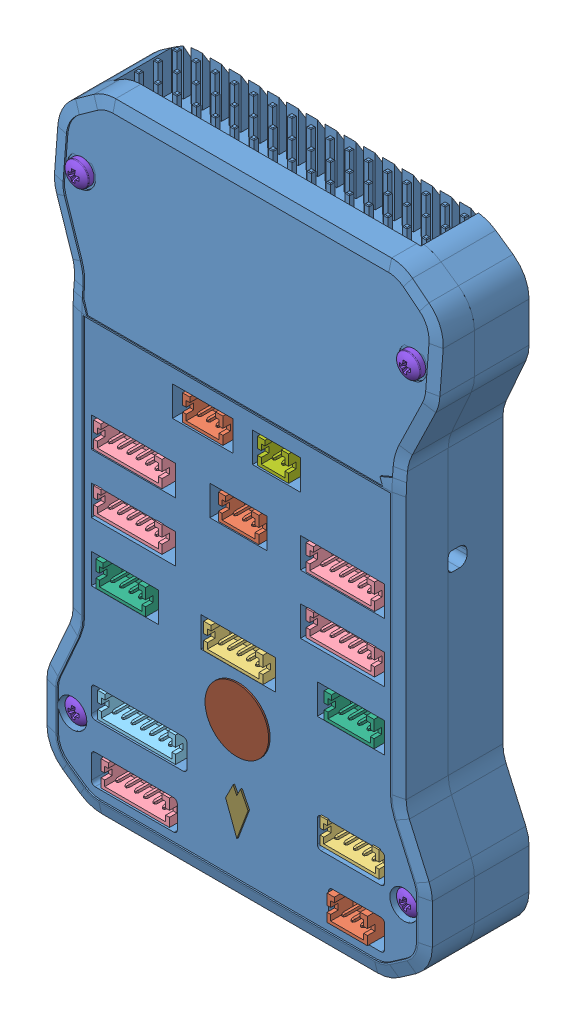
SolidWorks assembly Pixhawk, configuration Défaut. Lengths in mm.
Overall size (63.92 81.8 15).
24 component instances, 12 part files, 56 mates.
Components (placement in the parent):
- Pixhawk APM-1: Pixhawk APM [Défaut] at (-25.3722 -39.1501 0) size (51.5 81.8 15)
- DF13-3P-1.25DSA-1: DF13-3P-1.25DSA [Défaut] at (-25.6222 -101.0173 12.2305) x (0 -1 0) z (-1 0 0) size (3.4 6.6 5.4)
- DF13-5P-1.25DSA-1: DF13-5P-1.25DSA [Défaut] at (-24.0615 -92.547 12.2305) x (0 -1 0) z (-1 0 0) size (3.4 6.6 7.9)
- DF13-6P-1.25DSA-1: DF13-6P-1.25DSA [Défaut] at (-52.0766 -100.5605 12.2305) x (0 -1 0) z (-1 0 0) size (3.4 6.6 9.15)
- DF13-7P-1.25DSA-1: DF13-7P-1.25DSA [Défaut] at (-51.2619 -92.8659 12.2305) x (0 -1 0) z (-1 0 0) size (3.4 6.6 10.4)
- DF13-4P-1.25DSA-1: DF13-4P-1.25DSA [Défaut] at (-24.742 -77.7939 12.2305) x (0 -1 0) z (-1 0 0) size (3.4 6.6 6.65)
- DF13-4P-1.25DSA-2: DF13-4P-1.25DSA [Défaut] at (-55.2674 -77.7939 12.2305) x (0 -1 0) z (-1 0 0) size (3.4 6.6 6.65)
- DF13-5P-1.25DSA-2: DF13-5P-1.25DSA [Défaut] at (-39.5965 -77.7939 12.2305) x (0 -1 0) z (-1 0 0) size (3.4 6.6 7.9)
- DF13-6P-1.25DSA-2: DF13-6P-1.25DSA [Défaut] at (-24.6722 -69.4608 12.2305) x (0 -1 0) z (-1 0 0) size (3.4 6.6 9.15)
- DF13-6P-1.25DSA-3: DF13-6P-1.25DSA [Défaut] at (-24.6722 -61.8649 12.2305) x (0 -1 0) z (-1 0 0) size (3.4 6.6 9.15)
- DF13-6P-1.25DSA-4: DF13-6P-1.25DSA [Défaut] at (-53.0678 -69.4608 12.2305) x (0 -1 0) z (-1 0 0) size (3.4 6.6 9.15)
- DF13-6P-1.25DSA-5: DF13-6P-1.25DSA [Défaut] at (-53.0678 -61.8649 12.2305) x (0 -1 0) z (-1 0 0) size (3.4 6.6 9.15)
- DF13-3P-1.25DSA-2: DF13-3P-1.25DSA [Défaut] at (-40.1316 -61.8649 12.2305) x (0 -1 0) z (-1 0 0) size (3.4 6.6 5.4)
- DF13-2P-1.25DSA-1: DF13-2P-1.25DSA [Défaut] at (-36.1541 -52.7875 12.2305) x (0 -1 0) z (-1 0 0) size (3.4 6.6 4.15)
- DF13-3P-1.25DSA-3: DF13-3P-1.25DSA [Défaut] at (-44.932 -52.7875 12.2305) x (0 -1 0) z (-1 0 0) size (3.4 6.6 5.4)
- pan head cross recess screw_iso-1: pan head cross recess screw_iso [ISO 7045 - M1.6 x 3 - Z --- 3N] at (-3.2222 -8.1001 14.8) x (0 0 -1) z (1 0 0) size (4.27 3.2 3.2)
- pan head cross recess screw_iso-2: pan head cross recess screw_iso [ISO 7045 - M1.6 x 3 - Z --- 3N] at (-47.5222 -8.1001 14.8) x (0 0 -1) z (1 0 0) size (4.27 3.2 3.2)
- pan head cross recess screw_iso-3: pan head cross recess screw_iso [ISO 7045 - M1.6 x 3 - Z --- 3N] at (-3.2222 -70.2001 14.8) x (0 0 -1) z (1 0 0) size (4.27 3.2 3.2)
- pan head cross recess screw_iso-4: pan head cross recess screw_iso [ISO 7045 - M1.6 x 3 - Z --- 3N] at (-47.5222 -70.2001 14.8) x (0 0 -1) z (1 0 0) size (4.27 3.2 3.2)
- micro USB-2: micro USB [Défaut] at (-63.1127 -36.7397 13.3569) x (0 1 0) z (-1 0 0) size (21.93 8.87 21.44)
  - micro usb02-1: micro usb02 [Défaut] at (-14.4796 6.4719 -20.7085) size (6.9 2.16 4.2)
  - micro USB-1: micro USB [Défaut] at (-14.4796 6.4719 -16.0085) size (7.99 2.94 5.43)
- pièce10^Pixhawk-1: pièce10^Pixhawk [Défaut] at (-25.3722 -39.1501 14.5) size (8.5 8.5 0.5) (virtual)
- pièce11^Pixhawk-1: pièce11^Pixhawk [Défaut] at (-25.3722 -39.1501 14.5) size (3 6 0.5) (virtual)
Mates (geometry in assembly coordinates):
- Coïncidente1: coincident aligned: plane of Pixhawk APM-1 through (-25.3722 -39.1501 15) normal (0 0 1); plane of DF13-3P-1.25DSA-1 through (-7.1722 -76.9001 15) normal (0 0 1)
- Parallèle1: coincident anti-aligned: plane of Pixhawk APM-1 through (-5.8222 -77.2001 10) normal (0 1 0); plane of DF13-3P-1.25DSA-1 through (-23.427 -77.2001 14.6158) normal (0 -1 0)
- Coïncidente2: coincident aligned: plane of Pixhawk APM-1 through (-25.3722 -39.1501 15) normal (0 0 1); plane of DF13-5P-1.25DSA-1 through (-13.7615 -65.9798 15) normal (0 0 1)
- Parallèle2: parallel anti-aligned: plane of Pixhawk APM-1 through (-5.8222 -69.5001 10) normal (0 1 0); plane of DF13-5P-1.25DSA-1 through (-9.3663 -68.7298 14.6158) normal (0 -1 0)
- Coïncidente4: coincident aligned: plane of Pixhawk APM-1 through (-25.3722 -39.1501 15) normal (0 0 1); plane of DF13-6P-1.25DSA-1 through (-43.0266 -73.9933 15) normal (0 0 1)
- Parallèle3: parallel anti-aligned: plane of Pixhawk APM-1 through (-33.5222 -77.2001 10) normal (0 1 0); plane of DF13-6P-1.25DSA-1 through (-38.6314 -76.7433 14.6158) normal (0 -1 0)
- Coïncidente5: coincident aligned: plane of Pixhawk APM-1 through (-25.3722 -39.1501 15) normal (0 0 1); plane of DF13-7P-1.25DSA-1 through (-47.8119 -68.7487 15) normal (0 0 1)
- Parallèle5: parallel anti-aligned: plane of Pixhawk APM-1 through (-32.2222 -69.5001 10) normal (0 1 0); plane of DF13-7P-1.25DSA-1 through (-49.0667 -69.0487 14.6158) normal (0 -1 0)
- Coïncidente6: coincident aligned: plane of Pixhawk APM-1 through (-25.3722 -39.1501 15) normal (0 0 1); plane of DF13-4P-1.25DSA-2 through (-51.8174 -53.6767 15) normal (0 0 1)
- Parallèle6: parallel anti-aligned: plane of Pixhawk APM-1 through (-36.0222 -54.2001 10) normal (0 1 0); plane of DF13-4P-1.25DSA-2 through (-39.3222 -53.9767 14.6158) normal (0 -1 0)
- Coïncidente7: coincident aligned: plane of Pixhawk APM-1 through (-25.3722 -39.1501 15) normal (0 0 1); plane of DF13-4P-1.25DSA-1 through (-21.292 -53.6767 15) normal (0 0 1)
- Coïncidente8: coincident aligned: plane of DF13-4P-1.25DSA-1 through (-8.7968 -53.9767 14.6158) normal (0 -1 0); plane of DF13-4P-1.25DSA-2 through (-39.3222 -53.9767 14.6158) normal (0 -1 0)
- Coïncidente9: coincident aligned: plane of Pixhawk APM-1 through (-25.3722 -39.1501 15) normal (0 0 1); plane of DF13-5P-1.25DSA-2 through (-36.1465 -53.6767 15) normal (0 0 1)
- Coïncidente10: coincident aligned: plane of DF13-4P-1.25DSA-2 through (-39.3222 -53.9767 14.6158) normal (0 -1 0); plane of DF13-5P-1.25DSA-2 through (-24.9013 -53.9767 14.6158) normal (0 -1 0)
- Coïncidente12: coincident aligned: plane of Pixhawk APM-1 through (-25.3722 -39.1501 15) normal (0 0 1); plane of DF13-6P-1.25DSA-2 through (-21.2222 -45.3436 15) normal (0 0 1)
- Parallèle8: parallel anti-aligned: plane of Pixhawk APM-1 through (-5.8222 -46.3001 10) normal (0 1 0); plane of DF13-6P-1.25DSA-2 through (-11.227 -45.6436 14.6158) normal (0 -1 0)
- Coïncidente13: coincident aligned: plane of DF13-6P-1.25DSA-2 through (-21.2222 -45.3436 15) normal (0 0 1); plane of DF13-6P-1.25DSA-3 through (-21.2222 -37.7478 15) normal (0 0 1)
- Coïncidente14: coincident aligned: plane of DF13-6P-1.25DSA-2 through (-6.9722 -44.1423 9.9583) normal (1 0 0); plane of DF13-6P-1.25DSA-3 through (-6.9722 -36.5465 9.9583) normal (1 0 0)
- Coïncidente15: coincident aligned: plane of Pixhawk APM-1 through (-25.3722 -39.1501 15) normal (0 0 1); plane of DF13-6P-1.25DSA-4 through (-44.0178 -42.8936 15) normal (0 0 1)
- Coïncidente16: coincident aligned: plane of DF13-6P-1.25DSA-2 through (-11.227 -45.6436 14.6158) normal (0 -1 0); plane of DF13-6P-1.25DSA-4 through (-39.6226 -45.6436 14.6158) normal (0 -1 0)
- Coïncidente17: coincident aligned: plane of Pixhawk APM-1 through (-25.3722 -39.1501 15) normal (0 0 1); plane of DF13-6P-1.25DSA-5 through (-44.0178 -35.2978 15) normal (0 0 1)
- Coïncidente18: coincident aligned: plane of DF13-6P-1.25DSA-3 through (-11.227 -38.0478 14.6158) normal (0 -1 0); plane of DF13-6P-1.25DSA-5 through (-39.6226 -38.0478 14.6158) normal (0 -1 0)
- Coïncidente19: coincident aligned: plane of DF13-6P-1.25DSA-4 through (-35.3678 -44.1423 9.9583) normal (1 0 0); plane of DF13-6P-1.25DSA-5 through (-35.3678 -36.5465 9.9583) normal (1 0 0)
- Coïncidente20: coincident aligned: plane of Pixhawk APM-1 through (-25.3722 -39.1501 15) normal (0 0 1); plane of DF13-3P-1.25DSA-2 through (-27.3316 -35.2978 15) normal (0 0 1)
- Coïncidente21: coincident aligned: plane of DF13-6P-1.25DSA-3 through (-11.227 -38.0478 14.6158) normal (0 -1 0); plane of DF13-3P-1.25DSA-2 through (-37.9364 -38.0478 14.6158) normal (0 -1 0)
- Coïncidente22: coincident aligned: plane of Pixhawk APM-1 through (-25.3722 -39.1501 15) normal (0 0 1); plane of DF13-2P-1.25DSA-1 through (-22.1041 -26.2203 15) normal (0 0 1)
- Parallèle9: parallel anti-aligned: plane of Pixhawk APM-1 through (-17.0722 -29.4001 10) normal (0 1 0); plane of DF13-2P-1.25DSA-1 through (-33.9589 -28.9703 14.6158) normal (0 -1 0)
- Coïncidente23: coincident aligned: plane of Pixhawk APM-1 through (-25.3722 -39.1501 15) normal (0 0 1); plane of DF13-3P-1.25DSA-3 through (-32.132 -26.2203 15) normal (0 0 1)
- Coïncidente24: coincident aligned: plane of DF13-2P-1.25DSA-1 through (-33.9589 -28.9703 14.6158) normal (0 -1 0); plane of DF13-3P-1.25DSA-3 through (-42.7368 -28.9703 14.6158) normal (0 -1 0)
- Coaxiale2: concentric aligned: cylinder of Pixhawk APM-1 through (-3.2222 -8.1001 7.5) axis (0 0 1) radius 1; cylinder of pan head cross recess screw_iso-1 through (-3.2222 -8.1001 40.2) axis (0 0 1) radius 1.6
- Coïncidente25: coincident anti-aligned: plane of Pixhawk APM-1 through (-3.2222 -8.1001 13.5) normal (0 0 1); plane of pan head cross recess screw_iso-1 through (-3.2222 -7.3001 13.5) normal (0 0 -1)
- Coaxiale3: concentric aligned: cylinder of Pixhawk APM-1 through (-47.5222 -8.1001 7.5) axis (0 0 1) radius 1; cylinder of pan head cross recess screw_iso-2 through (-47.5222 -8.1001 40.2) axis (0 0 1) radius 1.6
- Coïncidente26: coincident anti-aligned: plane of Pixhawk APM-1 through (-47.5222 -8.1001 13.5) normal (0 0 1); plane of pan head cross recess screw_iso-2 through (-47.5222 -7.3001 13.5) normal (0 0 -1)
- Coaxiale4: concentric aligned: cylinder of Pixhawk APM-1 through (-3.2222 -70.2001 7.5) axis (0 0 1) radius 1; cylinder of pan head cross recess screw_iso-3 through (-3.2222 -70.2001 40.2) axis (0 0 1) radius 1.6
- Coïncidente27: coincident anti-aligned: plane of Pixhawk APM-1 through (-3.2222 -70.2001 13.5) normal (0 0 1); plane of pan head cross recess screw_iso-3 through (-3.2222 -69.4001 13.5) normal (0 0 -1)
- Coaxiale5: concentric aligned: cylinder of Pixhawk APM-1 through (-47.5222 -70.2001 7.5) axis (0 0 1) radius 1; cylinder of pan head cross recess screw_iso-4 through (-47.5222 -70.2001 40.2) axis (0 0 1) radius 1.6
- Coïncidente28: coincident anti-aligned: plane of Pixhawk APM-1 through (-47.5222 -70.2001 13.5) normal (0 0 1); plane of pan head cross recess screw_iso-4 through (-47.5222 -69.4001 13.5) normal (0 0 -1)
- Parallèle10: coincident aligned: plane of Pixhawk APM-1 through (-41.6222 -47.1801 5.66) normal (0 0 1); plane of micro USB-2/micro USB-1 through (-42.4042 -54.4194 5.66) normal (0 0 1)
- Parallèle11: parallel anti-aligned: line of Pixhawk APM-1 through (-47.6222 -47.6801 5.66) axis (0 -1 0); line of micro USB-2/micro USB-1 through (-47.528 -54.2194 5.6099) axis (0 1 0)
- Sur place1: in place: plane of Pixhawk APM-1 through (-0.7222 -19.1501 14.5) normal (0 0 1); plane of ? through (0 0 14.5) normal (0 0 1); moOrthogonalPlaneRef_w of Pixhawk APM-1 through (-0.7222 -19.1501 14.5) normal (0 0 1); plane of ? through (0 0 14.5) normal (0 1 0); plane of Pixhawk APM-1 through (-0.7222 -19.1501 14.5) normal (0 0 1); plane of ? through (0 0 14.5) normal (1 0 0); plane of Pixhawk APM-1 through (-25.3722 -59.8001 14.5) normal (0 0 1); unknown of ?
- Coïncidente29: coincident aligned: plane of Pixhawk APM-1; plane of pièce10^Pixhawk-1
- Coïncidente30: coincident aligned: moOrthogonalPlaneRef_w of Pixhawk APM-1 through (-25.3722 -39.1501 14.5) normal (0 1 0); plane of pièce10^Pixhawk-1 through (-25.3722 -39.1501 14.5) normal (0 1 0)
- Coïncidente31: coincident anti-aligned: moOrthogonalPlaneRef_w of Pixhawk APM-1 through (-25.3722 -39.1501 14.5) normal (-1 0 0); plane of pièce10^Pixhawk-1 through (-25.3722 -39.1501 14.5) normal (1 0 0)
- Sur place2: in place: plane of Pixhawk APM-1 through (-25.3722 -39.1501 14.5) normal (0 0 1); plane of ? through (0 0 14.5) normal (0 0 1); plane of Pixhawk APM-1 through (-25.3722 -39.1501 14.5) normal (0 0 1); plane of ? through (0 0 14.5) normal (0 1 0); plane of Pixhawk APM-1 through (-25.3722 -39.1501 14.5) normal (0 0 1); plane of ? through (0 0 14.5) normal (1 0 0); plane of Pixhawk APM-1 through (-25.3722 -39.1501 14.5) normal (0 0 1); unknown of ?
- Coïncidente32: coincident aligned: plane of Pixhawk APM-1; plane of pièce11^Pixhawk-1
- Coïncidente33: coincident aligned: moOrthogonalPlaneRef_w of Pixhawk APM-1 through (-25.3722 -39.1501 14.5) normal (0 1 0); plane of pièce11^Pixhawk-1 through (-25.3722 -39.1501 14.5) normal (0 1 0)
- Coïncidente34: coincident anti-aligned: moOrthogonalPlaneRef_w of Pixhawk APM-1 through (-25.3722 -39.1501 14.5) normal (-1 0 0); plane of pièce11^Pixhawk-1 through (-25.3722 -39.1501 14.5) normal (1 0 0)
- Sur place3: in place: plane of Pixhawk APM-1 through (-25.3722 18.1083 14.5017) normal (0 0.083045 0.996546); plane of ? through (0 1.325 15.9003) normal (0 0.083045 0.996546); plane of Pixhawk APM-1 through (-25.3722 18.1083 14.5017) normal (0 0.083045 0.996546); plane of ? through (0 1.325 15.9003) normal (0 0.996546 -0.083045); plane of Pixhawk APM-1 through (-25.3722 18.1083 14.5017) normal (0 0.083045 0.996546); unknown of ?; plane of Pixhawk APM-1 through (-25.3722 18.1083 14.5017) normal (0 0.083045 0.996546); unknown of ?
- Coïncidente35: coincident aligned: plane of Pixhawk APM-1; plane of ?
- Coïncidente36: coincident aligned: moOrthogonalPlaneRef_w of Pixhawk APM-1 through (-25.3722 -37.5551 19.1403) normal (0 0.996546 -0.083045); plane of ? through (-25.3722 -37.5551 19.1403) normal (0 0.996546 -0.083045)
- Coïncidente37: coincident anti-aligned: moOrthogonalPlaneRef_w of Pixhawk APM-1 through (-25.3722 -37.5551 19.1403) normal (-1 0 0); plane of ?
- Sur place4: in place: plane of Pixhawk APM-1 through (-25.3722 18.1083 14.5017) normal (0 0.083045 0.996546); plane of ? through (0 1.325 15.9003) normal (0 0.083045 0.996546); plane of Pixhawk APM-1 through (-25.3722 18.1083 14.5017) normal (0 0.083045 0.996546); plane of ? through (0 1.325 15.9003) normal (0 0.996546 -0.083045); plane of Pixhawk APM-1 through (-25.3722 18.1083 14.5017) normal (0 0.083045 0.996546); unknown of ?; plane of Pixhawk APM-1 through (-25.3722 18.1083 14.5017) normal (0 0.083045 0.996546); unknown of ?
- Coïncidente38: coincident aligned: plane of Pixhawk APM-1; plane of ?
- Coïncidente39: coincident aligned: moOrthogonalPlaneRef_w of Pixhawk APM-1 through (-25.3722 -37.5551 19.1403) normal (0 0.996546 -0.083045); plane of ? through (-25.3722 -37.5551 19.1403) normal (0 0.996546 -0.083045)
- Coïncidente40: coincident anti-aligned: moOrthogonalPlaneRef_w of Pixhawk APM-1 through (-25.3722 -37.5551 19.1403) normal (-1 0 0); plane of ?
- 重合/共線/共點2: coincident anti-aligned: plane of Pixhawk APM-1 through (-13.3222 -77.2001 10) normal (1 0 0); plane of DF13-3P-1.25DSA-1 through (-13.3222 -75.6988 9.9583) normal (-1 0 0)
